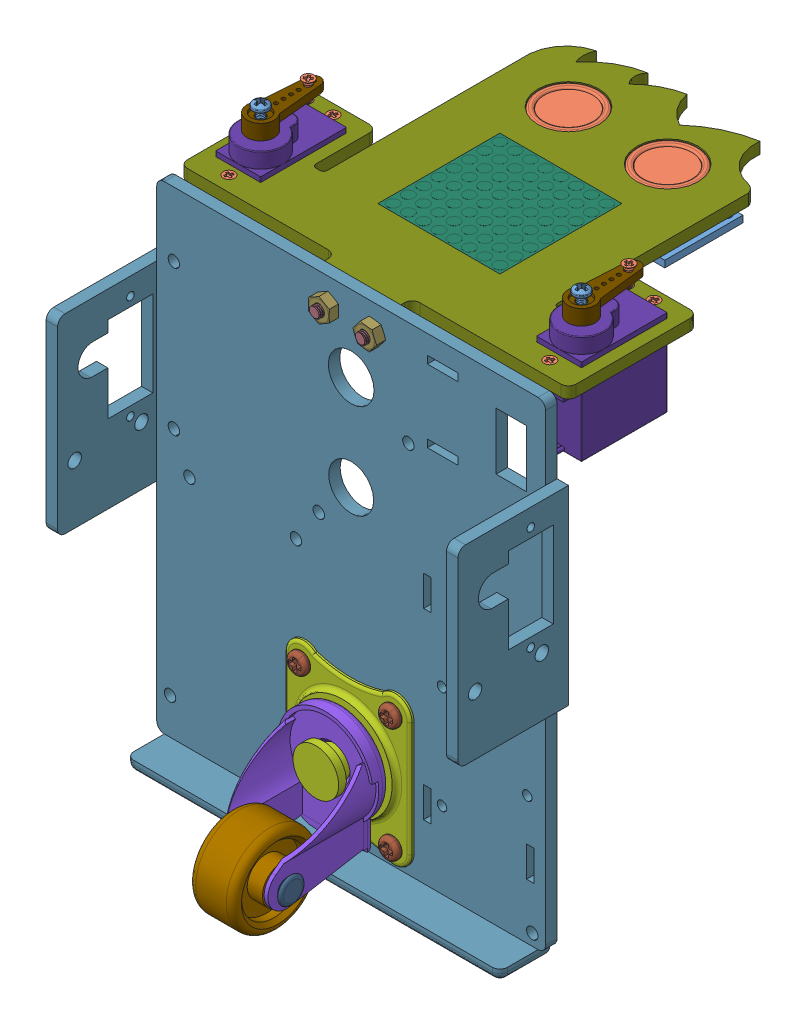
SolidWorks assembly DYOR_3D_LM_AC, configuration Predeterminado. Lengths in mm.
Overall size (108 144.05 125.97).
49 component instances, 20 part files, 19 mates.
Components (placement in the parent):
- HC-SR04 Ping Sensor-1: HC-SR04 Ping Sensor [Default] at (9.418 28.7888 -57.4611) x (0 0 -1) z (0 1 0) size (25.18 45 18.07)
  - PCB-1: PCB [Default] at origin size (20.5 45 1.75)
  - Transducer-1: Transducer [Default] at (0 -13 13.25) x (1 0 0) z (0 -1 0) size (15.88 12 15.88)
  - Transducer-2: Transducer [Default] at (0 13 13.25) x (1 0 0) z (0 -1 0) size (15.88 12 15.88)
  - 3 Pin Header 90 Degree-1: 3 Pin Header 90 Degree [Default] at (8.4275 0 -1.25) x (-1 0 0) z (0 -1 0) size (8 7.82 10)
  - 14 Pin SMT-1: 14 Pin SMT [Default] at (-0.35 -18.5 -0.85) x (0 -1 0) z (1 0 0) size (6 1.6 8.8)
  - 14 Pin SMT-2: 14 Pin SMT [Default] at (0 -0.3826 -0.85) x (1 0 0) z (0 1 0) size (6 1.6 8.8)
  - 14 Pin SMT-3: 14 Pin SMT [Default] at (0 17.5274 -0.85) x (1 0 0) z (0 1 0) size (6 1.6 8.8)
  - Cap1 SMT-1: Cap1 SMT [Default] at (-1.755 7.4774 -0.9689) x (0 1 0) z (-1 0 0) size (4.5 1.84 1.75)
  - Cap1 SMT-2: Cap1 SMT [Default] at (6.835 7.4774 -0.9689) x (0 1 0) z (-1 0 0) size (4.5 1.84 1.75)
  - Cap1 SMT-3: Cap1 SMT [Default] at (-6.835 7.4774 -0.9689) x (0 1 0) z (-1 0 0) size (4.5 1.84 1.75)
  - Cap1 SMT-4: Cap1 SMT [Default] at (4.295 7.4774 -0.9689) x (0 1 0) z (-1 0 0) size (4.5 1.84 1.75)
  - Cap1 SMT-5: Cap1 SMT [Default] at (1.755 7.4774 -0.9689) x (0 1 0) z (-1 0 0) size (4.5 1.84 1.75)
  - Cap1 SMT-6: Cap1 SMT [Default] at (-4.295 7.4774 -0.9689) x (0 1 0) z (-1 0 0) size (4.5 1.84 1.75)
  - HC-SR04 Crystal-1: HC-SR04 Crystal [Default] at (-8.3 0 1.75) x (0 -1 0) z (0 0 1) size (10 3.5 2.7)
- CA-1: CA [Predeterminado] at (-2.207 18.0036 0) size (33 45.94 43.2)
  - Caster Wheel-1: Caster Wheel [Default] at (57.6387 -78.841 57.7572) x (0 1 0) z (-1 0 0) size (45.94 37.59 33)
    - caster holder-1: caster holder [Default] at (-24.0751 44.7184 29.5137) x (1 0 0) z (0 0 -1) size (39 9.27 33)
    - holder-1: holder [Default] at (-1.5751 42.9484 46.0137) x (0 0 1) z (1 0 0) size (25 28.07 31.31)
    - caster wheel-1: caster wheel [Default] at (-15.6961 19.9484 46.0137) x (0.997275 0.073773 0) z (0 0 1) size (23 23 14)
    - Part4-1: Part4 [Default] at (-15.6961 19.9484 55.0137) x (-0.978448 0.206495 0) z (0 0 -1) size (7 7 20)
  - M3x6 Philips Screw-1: M3x6 Philips Screw [Predeterminado] at (23.625 -65.4161 13.5389) size (5.3 5.3 7.81)
  - M3x6 Philips Screw-2: M3x6 Philips Screw [Predeterminado] at (-0.375 -65.4161 13.5389) size (5.3 5.3 7.81)
  - M3x6 Philips Screw-3: M3x6 Philips Screw [Predeterminado] at (-0.375 -95.4161 13.5389) size (5.3 5.3 7.81)
  - M3x6 Philips Screw-4: M3x6 Philips Screw [Predeterminado] at (23.625 -95.4161 13.5389) size (5.3 5.3 7.81)
  - M3 Nut-1: M3 Nut [Predeterminado] at (23.625 -65.4161 11.0389) size (6.27 6.27 2.71)
  - M3 Nut-2: M3 Nut [Predeterminado] at (-0.375 -65.4161 11.0389) size (6.27 6.27 2.71)
  - M3 Nut-3: M3 Nut [Predeterminado] at (-0.375 -95.4161 11.0389) size (6.27 6.27 2.71)
  - M3 Nut-4: M3 Nut [Predeterminado] at (23.625 -95.4161 11.0389) size (6.27 6.27 2.71)
- M3x10 Philips Screw-2: M3x10 Philips Screw [Predeterminado] at (3.418 36.0388 6.1705) x (-0.582954 -0.812505 0) z (0 0 -1) size (5.3 5.3 11.8)
- M3x10 Philips Screw-3: M3x10 Philips Screw [Predeterminado] at (15.418 36.0388 6.1705) x (-0.89856 -0.438851 0) z (0 0 -1) size (5.3 5.3 11.8)
- M3 Nut-1: M3 Nut [Predeterminado] at (3.418 36.0388 16.5389) size (6.27 6.27 2.71)
- M3 Nut-2: M3 Nut [Predeterminado] at (15.418 36.0388 11.0389) x (-0.923728 -0.383049 0) z (0 0 -1) size (6.27 6.27 2.71)
- Base-1: Base [Predeterminado] at (60.418 -80.9125 12.5389) size (108 128.45 29)
- max7219_compact_board-1: max7219_compact_board [Predeterminado] at (15.918 28.3388 -26.4611) x (1 0 0) z (0 1 0) size (34 32 21.83)
- Front_LM_AC-1: Front_LM_AC [Predeterminado] at (-49.2809 39.5388 -46.4821) x (1 0 0) z (0 1 0) size (101.94 85.39 11)
- AC-1: AC [Predeterminado] at (-137.3228 216.8523 -134.1392) size (95.94 34.06 31.9)
  - sg90-1: sg90 [Default] at (182.9409 -195.7135 134.2781) x (0 0 -1) z (1 0 0) size (31.9 29.9 11.8)
  - sg90-2: sg90 [Default] at (98.7972 -195.7135 134.2781) x (0 0 -1) z (1 0 0) size (31.9 29.9 11.8)
  - SG90 plastic Horn-1: SG90 plastic Horn [Default] at (188.8409 -166.2635 128.3781) x (-0.029359 0 -0.999569) z (0.999569 0 -0.029359) size (19.4 4 7.07)
  - SG90 plastic Horn-2: SG90 plastic Horn [Default] at (104.6972 -166.2635 128.3781) x (-0.012387 0 -0.999923) z (0.999923 0 -0.012387) size (19.4 4 7.07)
  - (M2_3_mm)_90116A007_METRIC 316 SS PAN HEAD PHILLIPS MACHINE SCREW-1: (M2_3_mm)_90116A007_METRIC 316 SS PAN HEAD PHILLIPS MACHINE SCREW [90116A007] at (104.6972 -166.2635 128.3781) x (-1 0 0) z (0 1 0) size (4 4 4.68)
  - (M2_3_mm)_90116A007_METRIC 316 SS PAN HEAD PHILLIPS MACHINE SCREW-2: (M2_3_mm)_90116A007_METRIC 316 SS PAN HEAD PHILLIPS MACHINE SCREW [90116A007] at (188.8409 -166.2635 128.3781) x (-1 0 0) z (0 1 0) size (4 4 4.68)
  - M2x6 SelfTap Screw-1: M2x6 SelfTap Screw [Predeterminado] at (104.6972 -162.7635 115.8781) x (0.825172 0 -0.564882) z (0 1 0) size (3.4 3.28 6)
  - M2x6 SelfTap Screw-2: M2x6 SelfTap Screw [Predeterminado] at (188.7787 -162.7635 115.8783) x (0.001298 0 -0.999999) z (0 1 0) size (3.4 3.28 6)
  - M2x6 SelfTap Screw-3: M2x6 SelfTap Screw [Predeterminado] at (104.6972 -174.3135 109.3781) x (-0.923728 0 -0.383049) z (0 1 0) size (3.4 3.28 6)
  - M2x6 SelfTap Screw-4: M2x6 SelfTap Screw [Predeterminado] at (104.6972 -174.3135 136.6781) x (-0.923728 0 -0.383049) z (0 1 0) size (3.4 3.28 6)
  - M2x6 SelfTap Screw-5: M2x6 SelfTap Screw [Predeterminado] at (188.8409 -174.3135 136.6781) x (0.923728 0 0.383049) z (0 1 0) size (3.4 3.28 6)
  - M2x6 SelfTap Screw-6: M2x6 SelfTap Screw [Predeterminado] at (188.8409 -174.3135 109.3781) x (0.923728 0 0.383049) z (0 1 0) size (3.4 3.28 6)
Mates (geometry in assembly coordinates):
- Concéntrica15: concentric: circle of CA-1/Caster Wheel-1/caster holder-1; circle of Base-1
- Coincidente14: coincident: plane of CA-1/M3 Nut-4 through (21.418 -77.4125 9.5389) normal (0 0 1); plane of Base-1 through (-39.582 40.5388 9.5389) normal (0 0 -1)
- Concéntrica16: concentric: circle of CA-1/M3 Nut-1; circle of Base-1
- Coincidente26: coincident: plane of M3 Nut-2 through (15.418 36.0388 12.5389) normal (0 0 -1); plane of Base-1 through (-39.582 40.5388 12.5389) normal (0 0 1)
- Coincidente27: coincident: plane of M3 Nut-1 through (3.418 36.0388 12.5389) normal (0 0 -1); plane of Base-1 through (-39.582 40.5388 12.5389) normal (0 0 1)
- Concéntrica22: concentric: circle of M3 Nut-1; circle of Base-1
- Concéntrica23: concentric: circle of M3 Nut-2; circle of Base-1
- Coincidente28: coincident: plane of Base-1 through (-39.582 40.5388 9.5389) normal (0 0 -1); plane of Front_LM_AC-1 through (-0.582 42.5388 9.5389) normal (0 0 1)
- Concéntrica24: concentric: circle of Base-1; circle of Front_LM_AC-1
- Paralelo1: parallel: plane of Base-1 through (-39.582 42.5388 9.5389) normal (0 1 0); plane of Front_LM_AC-1 through (21.418 42.5388 8.5389) normal (0 1 0)
- Coincidente30: coincident: plane of max7219_compact_board-1 through (-6.582 42.5388 -10.4611) normal (0 0 1); plane of Front_LM_AC-1 through (-6.582 42.5388 -10.4611) normal (0 0 -1)
- Concéntrica25: concentric: circle of HC-SR04 Ping Sensor-1/Transducer-1; circle of Front_LM_AC-1
- Concéntrica26: concentric: circle of HC-SR04 Ping Sensor-1/Transducer-2; circle of Front_LM_AC-1
- Coincidente31: coincident: plane of HC-SR04 Ping Sensor-1/Transducer-2 through (-3.582 42.5388 -65.4011) normal (0 1 0); plane of Front_LM_AC-1 through (21.418 42.5388 8.5389) normal (0 1 0)
- Coincidente32: coincident: plane of max7219_compact_board-1 through (15.918 42.5388 -26.4611) normal (0 1 0); plane of Front_LM_AC-1 through (21.418 42.5388 8.5389) normal (0 1 0)
- Coincidente33: coincident: plane of max7219_compact_board-1 through (-6.582 42.5388 -42.4611) normal (-1 0 0); plane of Front_LM_AC-1 through (-6.582 42.5388 -42.4611) normal (1 0 0)
- Coincidente34: coincident: plane of Front_LM_AC-1 through (21.418 39.5388 8.5389) normal (0 -1 0); plane of AC-1/sg90-1 through (57.418 39.5388 -27.0611) normal (0 1 0)
- Coincidente35: coincident: circle of Front_LM_AC-1; circle of AC-1/M2x6 SelfTap Screw-3
- Coincidente36: coincident: plane of Front_LM_AC-1 through (57.418 42.5388 0.1389) normal (-1 0 0); plane of AC-1/sg90-1 through (57.418 21.1388 0.1389) normal (1 0 0)
